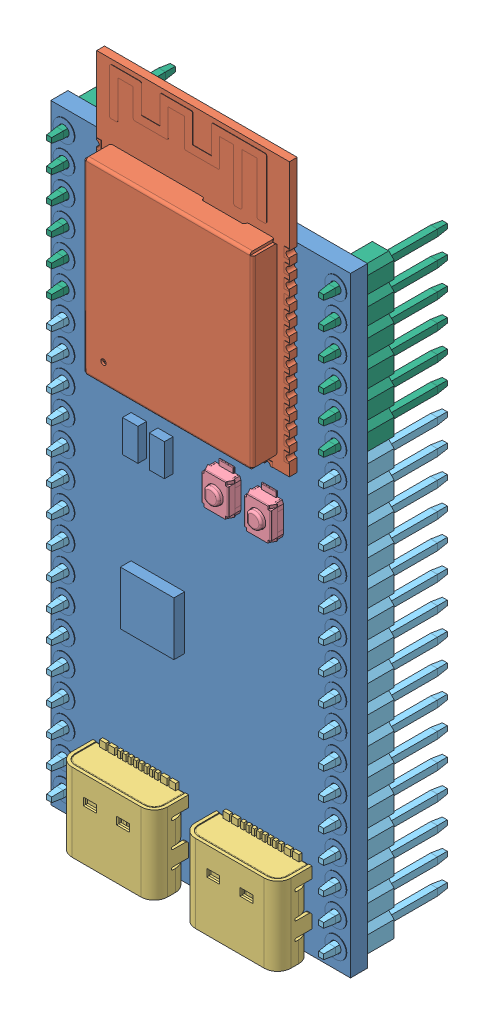
SolidWorks assembly AI-S3-DEVBOARD, configuration Défaut. Lengths in mm.
Overall size (28.01 63.95 13.41).
13 component instances, 6 part files, 0 mates.
Components (placement in the parent):
- AI-S3-DEVBOARD.STEP-1: AI-S3-DEVBOARD.STEP [Défaut] at origin size (28.01 63.95 13.41)
  - AI-S3-3D.STEP-1: AI-S3-3D.STEP [Défaut] at (-24.0748 30.9767 0.775) size (28 57 2.6)
  - ESP32-S3-WROOM-1.STEP-1: ESP32-S3-WROOM-1.STEP [Défaut] at (-18.8039 7.0995 0.74) size (18.46 25.51 4.01)
  - USB Type C Port (SMD Type).STEP-1: USB Type C Port (SMD Type).STEP [Défaut] at (-15.4148 -24.0435 2.38) x (1 0 0) z (0 0 -1) size (8.94 7.9 4.2)
  - USB Type C Port (SMD Type).STEP-2: USB Type C Port (SMD Type).STEP [Défaut] at (-3.8933 -24.0435 2.38) x (1 0 0) z (0 0 -1) size (8.94 7.9 4.2)
  - B3U1000P.STEP-1: B3U1000P.STEP [Défaut] at (-7.3146 2.6409 0.775) x (0 1 0) z (1 0 0) size (4 1.61 2.5)
  - B3U1000P.STEP-2: B3U1000P.STEP [Défaut] at (-3.3416 2.6961 0.775) x (0 1 0) z (1 0 0) size (4 1.61 2.5)
  - header.STEP-1: header.STEP [Défaut] at (2.8407 -11.6719 -0.825) x (0 1 0) z (-1 0 0) size (20.32 11.54 2.54)
  - header.STEP-2: header.STEP [Défaut] at (2.8407 8.6481 -0.825) x (0 1 0) z (-1 0 0) size (20.32 11.54 2.54)
  - header4.STEP-1: header4.STEP [Défaut] at (2.8407 23.8881 -0.825) x (0 1 0) z (-1 0 0) size (15.24 11.54 2.54)
  - header.STEP-3: header.STEP [Défaut] at (-22.5688 -11.6719 -0.825) x (0 1 0) z (-1 0 0) size (20.32 11.54 2.54)
  - header.STEP-4: header.STEP [Défaut] at (-22.5688 8.6481 -0.825) x (0 1 0) z (-1 0 0) size (20.32 11.54 2.54)
  - header4.STEP-2: header4.STEP [Défaut] at (-22.5688 23.8881 -0.825) x (0 1 0) z (-1 0 0) size (15.24 11.54 2.54)
